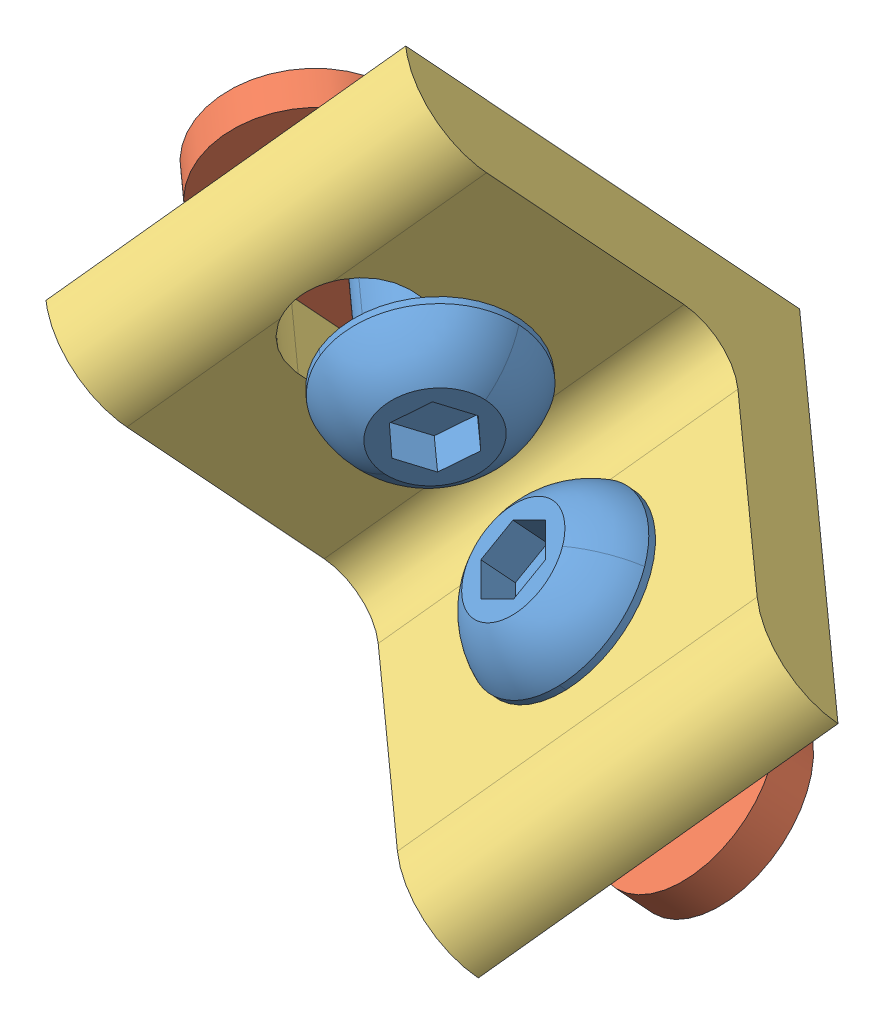
SolidWorks assembly corner connector, configuration Default. Lengths in mm.
Overall size (41.38 38.59 43.11).
5 component instances, 3 part files, 10 mates.
Components (placement in the parent):
- 3061-1: 3061 [Default] at (41.7523 27.0126 -0.6186) x (-0.738908 0.198729 -0.643834) z (0.521675 -0.436036 -0.733299) size (16.05 11.1 11.1)
- 3382-1: 3382 [Default] at (35.6714 28.6481 -5.917) x (0.354136 -0.698365 -0.621992) z (-0.738908 0.198729 -0.643834) size (25.4 11.25 3.15)
- 4265-1: 4265 [Default] at (42.7402 19.0873 -11.5759) x (0.573239 0.6876 -0.44565) z (0.738908 -0.198729 0.643834) size (22.23 25.4 25.4)
- 3382-2: 3382 [Default] at (53.3566 14.1333 -5.5637) x (-0.738908 0.198729 -0.643834) z (0.354136 -0.698365 -0.621992) size (25.4 11.25 3.15)
- 3061-2: 3061 [Default] at (50.4422 19.8806 -0.4449) x (0.354136 -0.698365 -0.621992) z (0.688116 -0.255815 0.679011) size (16.05 11.1 11.1)
Mates (geometry in assembly coordinates):
- Concentric1: concentric aligned: cylinder of 4265-1 through (49.2279 22.2753 1.6879) axis (0.354136 -0.698365 -0.621992) radius 3.5687; cylinder of 3061-2 through (55.7493 9.4149 -9.7661) axis (0.354136 -0.698365 -0.621992) radius 3.175
- Coincident2: coincident anti-aligned: plane of 4265-1 through (54.0934 26.874 -9.8935) normal (-0.354136 0.698365 0.621992); plane of 3061-2 through (54.7666 21.994 -4.031) normal (0.354136 -0.698365 -0.621992)
- Concentric3: concentric aligned: cylinder of 3061-1 through (33.1777 27.94 -10.2171) axis (-0.738908 0.198729 -0.643834) radius 3.175; cylinder of 4265-1 through (44.3167 24.9442 -0.5114) axis (-0.738908 0.198729 -0.643834) radius 3.5687
- Coincident3: coincident anti-aligned: plane of 3061-1 through (44.9287 30.2874 -3.2532) normal (-0.738908 0.198729 -0.643834); plane of 4265-1 through (46.1165 38.6093 -2.0477) normal (0.738908 -0.198729 0.643834)
- Concentric5: concentric anti-aligned: cylinder of 3061-1 through (33.1777 27.94 -10.2171) axis (-0.738908 0.198729 -0.643834) radius 3.175; cylinder of 3382-1 through (37.363 26.8144 -6.5703) axis (0.738908 -0.198729 0.643834) radius 2.4879
- Distance1: distance = 2.286 mm anti-aligned: plane of 3382-1 through (34.0484 33.351 -0.7485) normal (0.738908 -0.198729 0.643834); plane of 4265-1 through (49.1103 26.7283 -16.5282) normal (-0.738908 0.198729 -0.643834)
- Parallel1: parallel aligned: line of 4265-1 through (55.9479 4.8022 8.3079) axis (-0.738908 0.198729 -0.643834); line of 3382-2 through (55.7812 8.0253 0.7555) axis (-0.738908 0.198729 -0.643834)
- Concentric9: concentric anti-aligned: cylinder of 3382-2 through (52.9338 14.967 -4.8211) axis (-0.354136 0.698365 0.621992) radius 2.4879; cylinder of 3061-2 through (55.7493 9.4149 -9.7661) axis (0.354136 -0.698365 -0.621992) radius 3.175
- Distance2: distance = 2.286 mm anti-aligned: plane of 4265-1 through (67.8785 21.6806 -0.1748) normal (0.354136 -0.698365 -0.621992); plane of 3382-2 through (58.1608 13.5612 -0.2667) normal (-0.354136 0.698365 0.621992)
- Parallel2: parallel aligned: line of 3382-1 through (36.6431 18.0057 -8.463) axis (-0.354136 0.698365 0.621992); line of 4265-1 through (37.1796 9.8499 -8.0455) axis (-0.354136 0.698365 0.621992)
